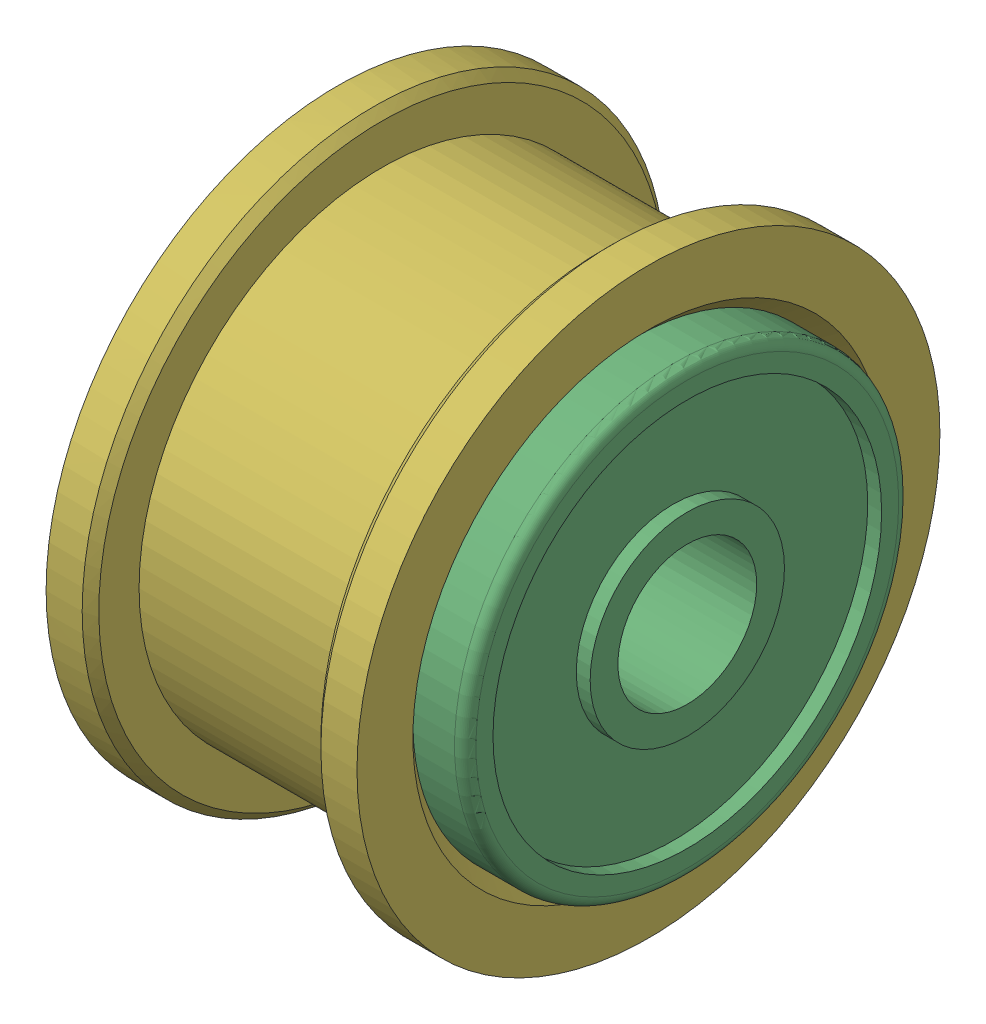
SolidWorks assembly 25197-02, configuration Default. Lengths in mm.
Overall size (12.6 21 21).
4 component instances, 3 part files, 0 mates.
Components (placement in the parent):
- 25201-01-1: 25201-01 [Default] at (36.6716 43.7387 22.0081) x (0 1 0) z (0 0 1) size (10 1 10)
- 25196-01-1: 25196-01 [Default] at (39.1716 43.7387 22.0081) x (0 1 0) z (0 0 1) size (16 5 16)
- 25196-01-2: 25196-01 [Default] at (33.1716 43.7387 22.0081) x (0 1 0) z (0 0 1) size (16 5 16)
- 25197-01-1: 25197-01 [Default] at (34.6716 43.7387 22.0081) size (11.2 21 21)
